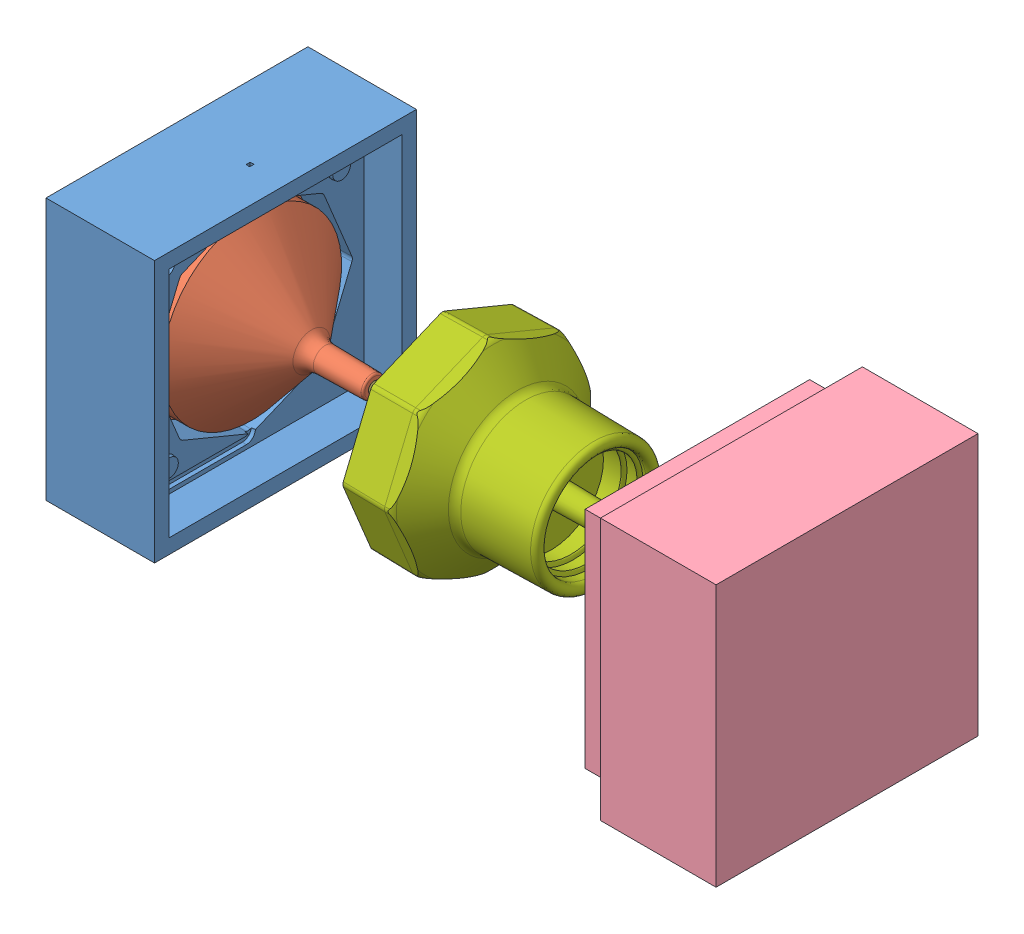
SolidWorks assembly FinalMold, configuration Default. Lengths in mm.
Overall size (179.08 70 70).
7 component instances, 7 part files, 22 mates.
Components (placement in the parent):
- Outside_PipeSide_WaxNegative-1: Outside_PipeSide_WaxNegative [Default] at origin size (29 70 70)
- Inside_PipeSide_3DPrintPositive_for_SiliconMold-1: Inside_PipeSide_3DPrintPositive_for_SiliconMold [Default] at origin size (44 53.56 53.56)
- Inside_PipeSide_SiliconNegative-1: Inside_PipeSide_SiliconNegative [Default] at origin size (44 46.26 44)
- Outside_BottleSide_WaxNegative-1: Outside_BottleSide_WaxNegative [Default] at (119.0784 0 0) size (41 70 70)
- Inside_BottleSide_3DPrintPositive_for_SiliconMold-1: Inside_BottleSide_3DPrintPositive_for_SiliconMold [Default] at (119.0784 0 0) size (17.68 34.5 34.5)
- Inside_BottleSide_SiliconNegative-1: Inside_BottleSide_SiliconNegative [Default] at (119.0784 0 0) size (18 31 31)
- multi-adapter-1: multi-adapter [Défaut] at (62.3085 0 0) size (44 55.22 55.22)
Mates (geometry in assembly coordinates):
- Coincident3: coincident aligned: line of ? through (-64.8429 0 0) axis (1 0 0); line of ? through (-27.5527 0 0) axis (1 0 0)
- Coincident4: coincident aligned: line of ? through (-64.8429 0 0) axis (1 0 0); line of ? through (-58.4594 0 0) axis (1 0 0)
- Coincident5: coincident aligned: plane of ? through (0.0022 0 0) normal (0 0 1); plane of assembly through (0 0 0) normal (0 0 1)
- Coincident6: coincident aligned: line of ? through (-64.8429 0 0) axis (1 0 0); line of ? through (-8.7282 0 0) axis (1 0 0)
- Coincident7: coincident aligned: plane of ? through (32.6853 0 0) normal (0 0 1); plane of assembly through (0 0 0) normal (0 0 1)
- Coincident8: coordinate: point of ?
- Coincident9: coincident aligned: line of Outside_PipeSide_WaxNegative-1 through (-58.4615 0 0) axis (1 0 0); line of Inside_PipeSide_3DPrintPositive_for_SiliconMold-1 through (-42 0 0) axis (1 0 0)
- Coincident10: coincident aligned: line of Outside_PipeSide_WaxNegative-1 through (-58.4615 0 0) axis (1 0 0); line of Inside_PipeSide_SiliconNegative-1 through (-64.8429 0 0) axis (1 0 0)
- Coincident11: coincident aligned: plane of Outside_PipeSide_WaxNegative-1 through (0 0 0) normal (0 0 1); plane of Inside_PipeSide_SiliconNegative-1 through (0 0 0) normal (0 0 1)
- Coincident12: coincident aligned: plane of Inside_PipeSide_3DPrintPositive_for_SiliconMold-1 through (0 0 0) normal (0 0 1); plane of assembly through (0 0 0) normal (0 0 1)
- Coincident13: coincident aligned: line of Outside_PipeSide_WaxNegative-1 through (-58.4615 0 0) axis (1 0 0); line of Outside_BottleSide_WaxNegative-1 through (60.6169 0 0) axis (1 0 0)
- Coincident14: coincident aligned: plane of Outside_BottleSide_WaxNegative-1 through (119.0784 0 0) normal (0 0 1); plane of assembly through (0 0 0) normal (0 0 1)
- Coincident15: coincident aligned: line of Outside_PipeSide_WaxNegative-1 through (-58.4615 0 0) axis (1 0 0); line of Inside_BottleSide_3DPrintPositive_for_SiliconMold-1 through (77.0784 0 0) axis (1 0 0)
- Coincident16: coincident aligned: plane of Outside_PipeSide_WaxNegative-1 through (0 0 0) normal (0 0 1); plane of Inside_BottleSide_3DPrintPositive_for_SiliconMold-1 through (119.0784 0 0) normal (0 0 1)
- Coincident17: coincident aligned: line of Outside_PipeSide_WaxNegative-1 through (-58.4615 0 0) axis (1 0 0); line of Inside_BottleSide_SiliconNegative-1 through (99.266 0 0) axis (1 0 0)
- Coincident18: coincident aligned: plane of Inside_BottleSide_SiliconNegative-1 through (119.0784 0 0) normal (0 0 1); plane of assembly through (0 0 0) normal (0 0 1)
- Coincident20: coincident anti-aligned: plane of Outside_PipeSide_WaxNegative-1 through (-42 0 -27) normal (1 0 0); plane of Inside_PipeSide_SiliconNegative-1 through (-42 0 -23) normal (-1 0 0)
- Coincident21: coincident anti-aligned: plane of Outside_PipeSide_WaxNegative-1 through (-42 0 -27) normal (1 0 0); plane of Inside_PipeSide_3DPrintPositive_for_SiliconMold-1 through (-42 0 -27) normal (-1 0 0)
- Coincident23: coincident aligned: line of Outside_PipeSide_WaxNegative-1 through (-58.4615 0 0) axis (1 0 0); line of multi-adapter-1 through (49.3085 0 0) axis (1 0 0)
- Coincident24: coincident aligned: plane of multi-adapter-1 through (62.3085 0 0) normal (0 0 1); plane of assembly through (0 0 0) normal (0 0 1)
- Coincident26: coincident anti-aligned: plane of Outside_BottleSide_WaxNegative-1 through (124.0784 15.5 0) normal (-1 0 0); plane of Inside_BottleSide_SiliconNegative-1 through (124.0784 15.5 0) normal (1 0 0)
- Coincident27: coincident anti-aligned: plane of Inside_BottleSide_3DPrintPositive_for_SiliconMold-1 through (106.0784 0 -5.2186) normal (1 0 0); plane of Inside_BottleSide_SiliconNegative-1 through (106.0784 0 -5.2186) normal (-1 0 0)
